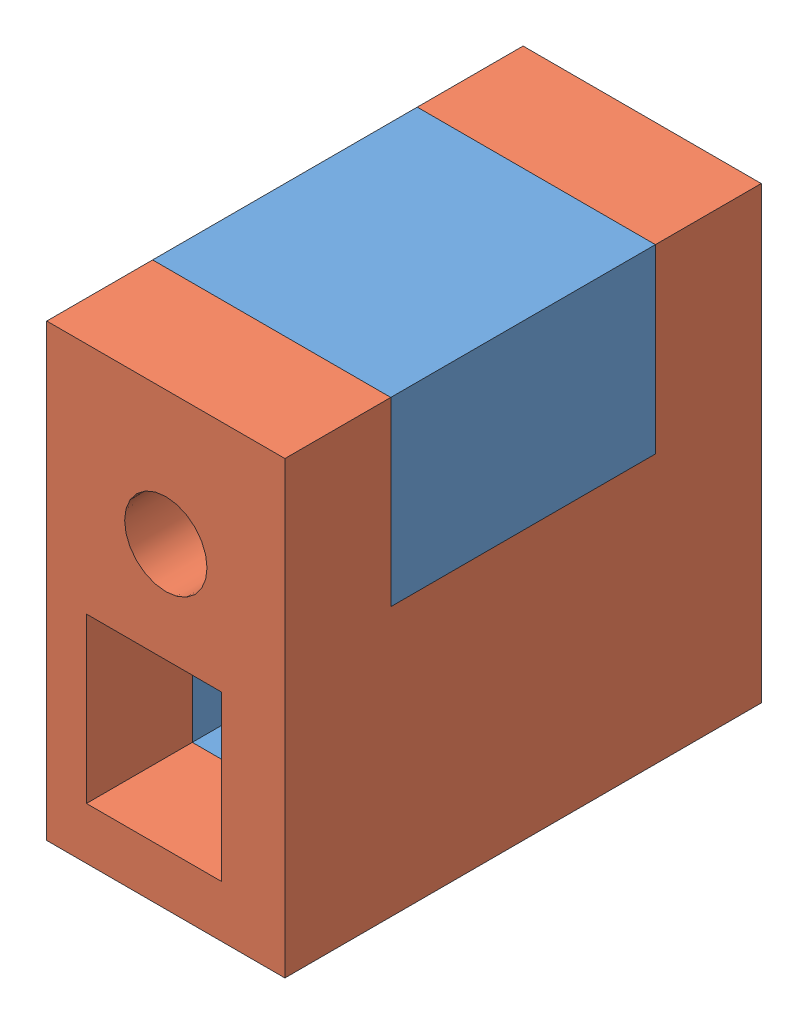
SolidWorks assembly belt_montage, configuration Standard. Lengths in mm.
Overall size (9 17 18).
2 component instances, 2 part files, 0 mates.
Components (placement in the parent):
- beltblock-1: beltblock [Standard] at (-79.562 -4.0106 27.6695) size (9 17 10)
- beltclipclip-1: beltclipclip [Standard] at (-70.02 19.942 19.5614) size (9 17 18)
